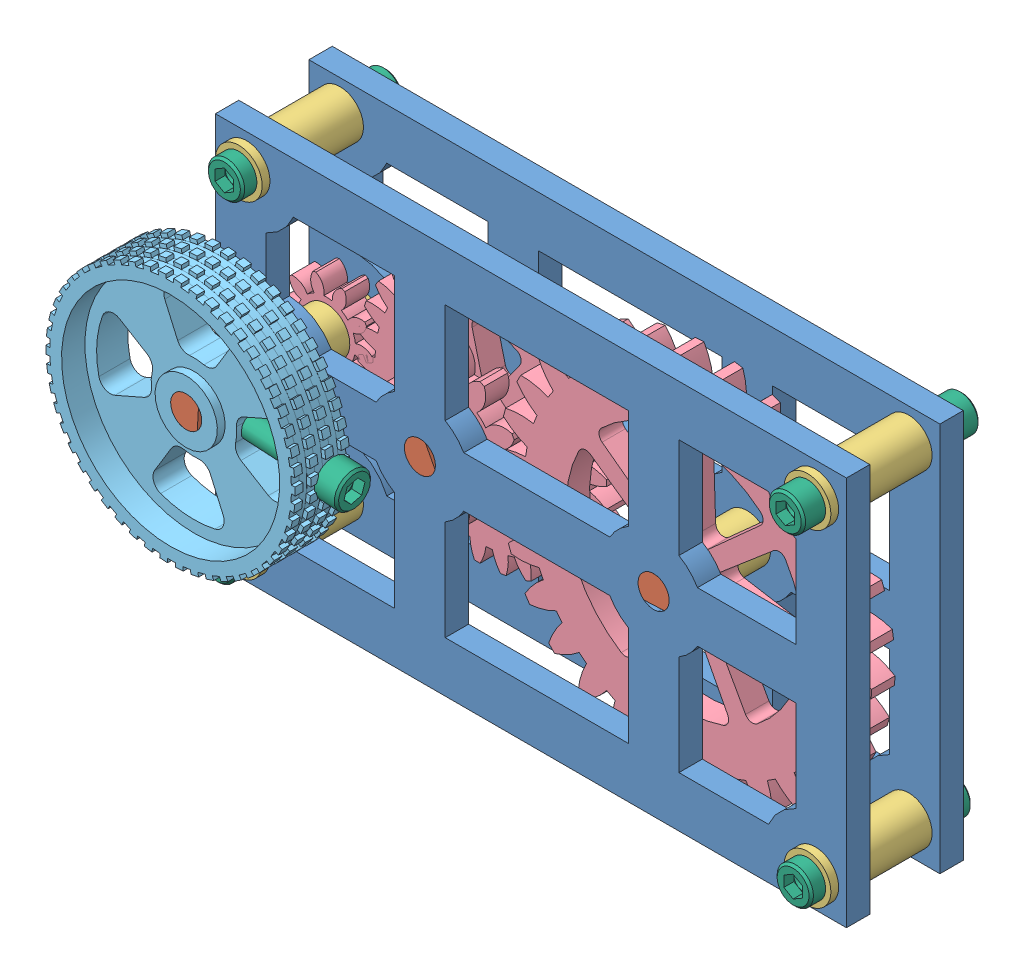
SolidWorks assembly Boxassem, configuration Default. Lengths in mm.
Overall size (91.84 50.13 37).
41 component instances, 6 part files, 57 mates.
Components (placement in the parent):
- gearbox-1: gearbox [Default] at (-8.9733 7.0729 77.188) size (81 50 3)
- subassem1-1: subassem1 [Default] at (-50.227 6.9916 109.6475) x (0.055794 0.998442 0) z (0 0 -1) size (11.53 12 25)
  - axle-1: axle [Long] at (0.4719 6.9883 7.4595) size (4 3.5 25)
  - spacer-1: spacer [1mm Tall] at (0.4719 6.9883 28.4595) x (0.18763 0.98224 0) z (0 0 1) size (6 6 1)
  - spacer-2: spacer [5mm Tall] at (0.4719 6.9883 20.4595) x (-0.596298 -0.802763 0) z (0 0 1) size (6 6 5)
  - root_gear-1: root_gear [10T 1.0Mod] at (0.4719 6.9883 25.4595) size (11.53 12 3)
- subassem2-1: subassem2 [Default] at (-30.4543 -3.0086 53.2509) x (0.46488 -0.885374 0) z (0 0 1) size (31.89 32 15)
  - axle-1: axle [Short] at (-5.5643 11.0888 23.9371) size (4 3.5 15)
  - root_gear-2: root_gear [30T 1.0Mod] at (-5.5643 11.0888 30.9371) x (-1 0 0) z (0 0 -1) size (31.89 32 3)
  - root_gear-3: root_gear [10T 1.5Mod] at (-5.5643 11.0888 31.9371) size (17.3 18 3)
  - spacer-1: spacer [1mm Tall] at (-5.5643 11.0888 34.9371) size (6 6 1)
  - spacer-2: spacer [1mm Tall] at (-5.5643 11.0888 30.9371) size (6 6 1)
  - spacer-3: spacer [4.2mm ID] at (-5.5643 11.0888 26.9371) size (6 6 1)
- subassem3-1: subassem3 [Default] at (11.1205 15.175 62.5804) x (-0.998971 -0.045347 0) z (0 0 1) size (47.84 48 25)
  - axle-1: axle [Long] at (4.7068 7.8968 4.6076) size (4 3.5 25)
  - root_gear-1: root_gear [30T 1.5Mod] at (4.7068 7.8968 22.6076) size (47.84 48 3)
  - spacer-1: spacer [4.2mm ID] at (4.7068 7.8968 25.6076) size (6 6 1)
  - spacer-3: spacer [5mm Tall] at (4.7068 7.8968 17.6076) size (6 6 5)
- gearbox-2: gearbox [Default] at (-8.9733 7.0729 89.188) size (81 50 3)
- knob-1: knob [Default] at (-43.2233 7.0729 97.188) x (0 0 1) z (-0.998442 0.055794 0) size (7 32 31.99)
- socket head cap screw_ai-8: socket head cap screw_ai [HX-SHCS 0.112-40x0.5625x0.5625-N] at (-24.62 6.0333 99.188) x (-0.998442 0.055794 0) z (-0.03971 -0.710622 0.702453) size (17.13 4.65 4.65)
- spacer-1: spacer [2.85mm ID] at (-45.4733 28.0729 80.188) size (6 6 9)
- spacer-2: spacer [1mm Tall] at (-45.4733 28.0729 92.188) x (0.882295 0.470697 0) z (0 0 1) size (6 6 1)
- spacer-3: spacer [2.85mm ID] at (-45.4733 -13.9271 80.188) size (6 6 9)
- spacer-4: spacer [1mm Tall] at (-45.4733 28.0729 76.188) x (0.877323 0.4799 0) z (0 0 1) size (6 6 1)
- spacer-5: spacer [2.85mm ID] at (27.5267 -13.9271 80.188) x (-0.974482 0.224464 0) z (0 0 1) size (6 6 9)
- spacer-6: spacer [2.85mm ID] at (27.5267 28.0729 80.188) x (0.88236 0.470576 0) z (0 0 1) size (6 6 9)
- spacer-7: spacer [1mm Tall] at (27.5267 28.0729 76.188) size (6 6 1)
- spacer-8: spacer [1mm Tall] at (27.5267 28.0729 92.188) size (6 6 1)
- spacer-9: spacer [1mm Tall] at (27.5267 -13.9271 76.188) x (0.973794 0.227431 0) z (0 0 1) size (6 6 1)
- spacer-10: spacer [1mm Tall] at (-45.4733 -13.9271 92.188) size (6 6 1)
- spacer-11: spacer [1mm Tall] at (27.5267 -13.9271 93.188) x (-0.923728 -0.383049 0) z (0 0 -1) size (6 6 1)
- spacer-12: spacer [1mm Tall] at (-45.4733 -13.9271 76.188) size (6 6 1)
- socket head cap screw_ai-11: socket head cap screw_ai [HX-SHCS 0.112-40x0.25x0.25-N] at (-45.4733 -13.9271 96.0328) x (0 0 -1) z (1 0 0) size (9.19 4.65 4.65)
- socket head cap screw_ai-12: socket head cap screw_ai [HX-SHCS 0.112-40x0.125x0.125-N] at (27.5267 -13.9271 95.0328) x (0 0 -1) z (1 0 0) size (6.02 4.65 4.65)
- socket head cap screw_ai-13: socket head cap screw_ai [HX-SHCS 0.112-40x0.125x0.125-N] at (27.5267 28.0729 96.0328) x (0 0 -1) z (1 0 0) size (6.02 4.65 4.65)
- socket head cap screw_ai-14: socket head cap screw_ai [HX-SHCS 0.112-40x0.125x0.125-N] at (-45.4733 28.0729 95.0328) x (0 0 -1) z (1 0 0) size (6.02 4.65 4.65)
- socket head cap screw_ai-16: socket head cap screw_ai [HX-SHCS 0.112-40x0.125x0.125-N] at (-45.4733 28.0729 74.3432) x (0 0 1) z (-1 0 0) size (6.02 4.65 4.65)
- socket head cap screw_ai-17: socket head cap screw_ai [HX-SHCS 0.112-40x0.125x0.125-N] at (27.5267 28.0729 73.3432) x (0 0 1) z (-1 0 0) size (6.02 4.65 4.65)
- socket head cap screw_ai-18: socket head cap screw_ai [HX-SHCS 0.112-40x0.125x0.125-N] at (27.5267 -13.9271 74.3432) x (0 0 1) z (-1 0 0) size (6.02 4.65 4.65)
- socket head cap screw_ai-20: socket head cap screw_ai [HX-SHCS 0.112-40x0.125x0.125-N] at (-45.4733 -13.9271 74.3432) x (0 0 1) z (-1 0 0) size (6.02 4.65 4.65)
Mates (geometry in assembly coordinates):
- Concentric1: concentric anti-aligned: cylinder of gearbox-1 through (-43.2233 7.0729 80.188) axis (0 0 -1) radius 2; cylinder of subassem1-1/axle-1 through (-43.2233 7.0729 77.188) axis (0 0 1) radius 2
- Coincident1: coincident anti-aligned: plane of gearbox-1 through (-8.9733 7.0729 80.188) normal (0 0 1); plane of subassem1-1/spacer-1 through (-43.2233 7.0729 80.188) normal (0 0 -1)
- Concentric2: concentric aligned: cylinder of gearbox-1 through (-23.2233 7.0729 80.188) axis (0 0 -1) radius 2; cylinder of subassem2-1/axle-1 through (-23.2233 7.0729 92.188) axis (0 0 -1) radius 2
- Coincident2: coincident anti-aligned: plane of gearbox-1 through (-8.9733 7.0729 80.188) normal (0 0 1); plane of subassem2-1/spacer-3 through (-23.2233 7.0729 80.188) normal (0 0 -1)
- GearMate1: gear = 10 : 30 mm: cylinder of subassem2-1/axle-1 through (-23.2233 7.0729 92.188) axis (0 0 -1) radius 2; cylinder of subassem1-1/axle-1 through (-43.2233 7.0729 77.188) axis (0 0 1) radius 2
- Parallel1: parallel aligned: plane of gearbox-1 through (-8.9733 7.0729 77.188) normal (0 0 -1); plane of subassem2-1/axle-1 through (-23.2233 7.0729 77.188) normal (0 0 -1)
- Concentric3: concentric aligned: cylinder of gearbox-1 through (6.7767 7.0729 80.188) axis (0 0 -1) radius 2; cylinder of subassem3-1/axle-1 through (6.7767 7.0729 92.188) axis (0 0 -1) radius 2
- Coincident4: coincident anti-aligned: plane of gearbox-1 through (-8.9733 7.0729 80.188) normal (0 0 1); plane of subassem3-1/spacer-3 through (6.7767 7.0729 80.188) normal (0 0 -1)
- GearMate2: gear = 10 : 30 mm: cylinder of subassem3-1/axle-1 through (6.7767 7.0729 92.188) axis (0 0 -1) radius 2; cylinder of subassem2-1/axle-1 through (-23.2233 7.0729 92.188) axis (0 0 -1) radius 2
- Concentric4: concentric aligned: cylinder of subassem3-1/axle-1 through (6.7767 7.0729 92.188) axis (0 0 -1) radius 2; cylinder of gearbox-2 through (6.7767 7.0729 92.188) axis (0 0 -1) radius 2
- Coincident5: coincident anti-aligned: plane of subassem3-1/spacer-1 through (6.7767 7.0729 89.188) normal (0 0 1); plane of gearbox-2 through (-8.9733 7.0729 89.188) normal (0 0 -1)
- Concentric5: concentric aligned: cylinder of subassem2-1/axle-1 through (-23.2233 7.0729 92.188) axis (0 0 -1) radius 2; cylinder of gearbox-2 through (-23.2233 7.0729 92.188) axis (0 0 -1) radius 2
- Concentric6: concentric anti-aligned: cylinder of subassem1-1/axle-1 through (-43.2233 7.0729 77.188) axis (0 0 1) radius 2; cylinder of knob-1 through (-43.2233 7.0729 97.188) axis (0 0 -1) radius 2
- Coincident6: coincident aligned: plane of subassem1-1/axle-1 through (-43.2233 7.0729 102.188) normal (0 0 1); plane of knob-1 through (-43.1117 9.0698 102.188) normal (0 0 1)
- Concentric7: concentric anti-aligned: cylinder of subassem1-1/axle-1 through (-43.2233 7.0729 77.188) axis (0 0 1) radius 2; cylinder of knob-1 through (-43.2233 7.0729 97.188) axis (0 0 -1) radius 2
- Concentric13: concentric anti-aligned: cylinder of knob-1 through (-43.2233 7.0729 99.188) axis (-0.998442 0.055794 0) radius 0.9; cylinder of socket head cap screw_ai-8 through (7.0805 4.2618 99.188) axis (0.998442 -0.055794 0) radius 1.4224
- Coincident12: coincident anti-aligned: plane of subassem1-1/axle-1 through (-41.7995 5.6684 77.188) normal (0.998442 -0.055794 0); plane of socket head cap screw_ai-8 through (-41.7666 6.257 98.445) normal (-0.998442 0.055794 0)
- Concentric15: concentric aligned: cylinder of gearbox-2 through (-45.4733 28.0729 92.188) axis (0 0 -1) radius 1.5; cylinder of spacer-2 through (-45.4733 28.0729 93.188) axis (0 0 -1) radius 2
- Coincident13: coincident anti-aligned: plane of gearbox-2 through (-8.9733 7.0729 92.188) normal (0 0 1); plane of spacer-2 through (-45.4733 28.0729 92.188) normal (0 0 -1)
- Concentric16: concentric aligned: cylinder of gearbox-1 through (-45.4733 28.0729 80.188) axis (0 0 -1) radius 1.5; cylinder of spacer-1 through (-45.4733 28.0729 89.188) axis (0 0 -1) radius 2
- Coincident14: coincident anti-aligned: plane of gearbox-1 through (-8.9733 7.0729 80.188) normal (0 0 1); plane of spacer-1 through (-45.4733 28.0729 80.188) normal (0 0 -1)
- Concentric17: concentric aligned: cylinder of gearbox-2 through (27.5267 28.0729 92.188) axis (0 0 -1) radius 1.5; cylinder of spacer-6 through (27.5267 28.0729 89.188) axis (0 0 -1) radius 2
- Coincident15: coincident anti-aligned: plane of gearbox-2 through (-8.9733 7.0729 89.188) normal (0 0 -1); plane of spacer-6 through (27.5267 28.0729 89.188) normal (0 0 1)
- Concentric18: concentric aligned: cylinder of gearbox-2 through (27.5267 -13.9271 92.188) axis (0 0 -1) radius 1.5; cylinder of spacer-5 through (27.5267 -13.9271 89.188) axis (0 0 -1) radius 2
- Coincident16: coincident anti-aligned: plane of gearbox-2 through (-8.9733 7.0729 89.188) normal (0 0 -1); plane of spacer-5 through (27.5267 -13.9271 89.188) normal (0 0 1)
- Concentric19: concentric aligned: cylinder of gearbox-2 through (-45.4733 -13.9271 92.188) axis (0 0 -1) radius 1.5; cylinder of spacer-3 through (-45.4733 -13.9271 89.188) axis (0 0 -1) radius 2
- Coincident17: coincident anti-aligned: plane of gearbox-2 through (-8.9733 7.0729 89.188) normal (0 0 -1); plane of spacer-3 through (-45.4733 -13.9271 89.188) normal (0 0 1)
- Concentric20: concentric aligned: cylinder of gearbox-1 through (-45.4733 28.0729 80.188) axis (0 0 -1) radius 1.5; cylinder of spacer-4 through (-45.4733 28.0729 77.188) axis (0 0 -1) radius 2
- Coincident18: coincident anti-aligned: plane of gearbox-1 through (-8.9733 7.0729 77.188) normal (0 0 -1); plane of spacer-4 through (-45.4733 28.0729 77.188) normal (0 0 1)
- Coincident19: coincident anti-aligned: plane of gearbox-1 through (-8.9733 7.0729 77.188) normal (0 0 -1); plane of spacer-7 through (27.5267 28.0729 77.188) normal (0 0 1)
- Concentric21: concentric aligned: cylinder of gearbox-1 through (27.5267 28.0729 80.188) axis (0 0 -1) radius 1.5; cylinder of spacer-7 through (27.5267 28.0729 77.188) axis (0 0 -1) radius 2
- Coincident20: coincident anti-aligned: plane of gearbox-2 through (-8.9733 7.0729 92.188) normal (0 0 1); plane of spacer-8 through (27.5267 28.0729 92.188) normal (0 0 -1)
- Concentric22: concentric aligned: cylinder of gearbox-2 through (27.5267 28.0729 92.188) axis (0 0 -1) radius 1.5; cylinder of spacer-8 through (27.5267 28.0729 93.188) axis (0 0 -1) radius 2
- Coincident22: coincident anti-aligned: plane of gearbox-2 through (-8.9733 7.0729 92.188) normal (0 0 1); plane of spacer-11 through (27.5267 -13.9271 92.188) normal (0 0 -1)
- Concentric23: concentric anti-aligned: cylinder of gearbox-2 through (27.5267 -13.9271 92.188) axis (0 0 -1) radius 1.5; cylinder of spacer-11 through (27.5267 -13.9271 92.188) axis (0 0 1) radius 2
- Concentric24: concentric aligned: cylinder of gearbox-1 through (27.5267 -13.9271 80.188) axis (0 0 -1) radius 1.5; cylinder of spacer-9 through (27.5267 -13.9271 77.188) axis (0 0 -1) radius 2
- Coincident23: coincident anti-aligned: plane of gearbox-1 through (-8.9733 7.0729 77.188) normal (0 0 -1); plane of spacer-9 through (27.5267 -13.9271 77.188) normal (0 0 1)
- Coincident24: coincident anti-aligned: plane of gearbox-1 through (-8.9733 7.0729 77.188) normal (0 0 -1); plane of spacer-12 through (-45.4733 -13.9271 77.188) normal (0 0 1)
- Coincident25: coincident anti-aligned: plane of gearbox-2 through (-8.9733 7.0729 92.188) normal (0 0 1); plane of spacer-10 through (-45.4733 -13.9271 92.188) normal (0 0 -1)
- Concentric25: concentric aligned: cylinder of gearbox-1 through (-45.4733 -13.9271 80.188) axis (0 0 -1) radius 1.5; cylinder of spacer-12 through (-45.4733 -13.9271 77.188) axis (0 0 -1) radius 2
- Concentric26: concentric aligned: cylinder of gearbox-2 through (-45.4733 -13.9271 92.188) axis (0 0 -1) radius 1.5; cylinder of spacer-10 through (-45.4733 -13.9271 93.188) axis (0 0 -1) radius 2
- Concentric27: concentric anti-aligned: cylinder of spacer-10 through (-45.4733 -13.9271 93.188) axis (0 0 -1) radius 2; cylinder of socket head cap screw_ai-11 through (-45.4733 -13.9271 127.7828) axis (0 0 1) radius 2.3241
- Coincident26: coincident anti-aligned: plane of spacer-10 through (-45.4733 -13.9271 93.188) normal (0 0 1); plane of socket head cap screw_ai-11 through (-45.4733 -11.603 93.188) normal (0 0 -1)
- Concentric28: concentric anti-aligned: cylinder of gearbox-2 through (27.5267 -13.9271 92.188) axis (0 0 -1) radius 1.5; cylinder of socket head cap screw_ai-12 through (27.5267 -13.9271 126.7828) axis (0 0 1) radius 2.3241
- Coincident27: coincident anti-aligned: plane of gearbox-2 through (-8.9733 7.0729 92.188) normal (0 0 1); plane of socket head cap screw_ai-12 through (27.5267 -11.603 92.188) normal (0 0 -1)
- Concentric29: concentric anti-aligned: cylinder of spacer-8 through (27.5267 28.0729 93.188) axis (0 0 -1) radius 2; cylinder of socket head cap screw_ai-13 through (27.5267 28.0729 127.7828) axis (0 0 1) radius 2.3241
- Coincident28: coincident anti-aligned: plane of spacer-8 through (27.5267 28.0729 93.188) normal (0 0 1); plane of socket head cap screw_ai-13 through (27.5267 30.397 93.188) normal (0 0 -1)
- Concentric30: concentric anti-aligned: cylinder of gearbox-2 through (-45.4733 28.0729 92.188) axis (0 0 -1) radius 1.5; cylinder of socket head cap screw_ai-14 through (-45.4733 28.0729 126.7828) axis (0 0 1) radius 2.3241
- Coincident29: coincident anti-aligned: plane of gearbox-2 through (-8.9733 7.0729 92.188) normal (0 0 1); plane of socket head cap screw_ai-14 through (-45.4733 30.397 92.188) normal (0 0 -1)
- Concentric32: concentric aligned: cylinder of gearbox-1 through (-45.4733 28.0729 80.188) axis (0 0 -1) radius 1.5; cylinder of socket head cap screw_ai-16 through (-45.4733 28.0729 42.5932) axis (0 0 -1) radius 2.3241
- Coincident31: coincident anti-aligned: plane of gearbox-1 through (-8.9733 7.0729 77.188) normal (0 0 -1); plane of socket head cap screw_ai-16 through (-45.4733 30.397 77.188) normal (0 0 1)
- Concentric33: concentric aligned: cylinder of spacer-7 through (27.5267 28.0729 77.188) axis (0 0 -1) radius 2; cylinder of socket head cap screw_ai-17 through (27.5267 28.0729 41.5932) axis (0 0 -1) radius 2.3241
- Coincident32: coincident anti-aligned: plane of spacer-7 through (27.5267 28.0729 76.188) normal (0 0 -1); plane of socket head cap screw_ai-17 through (27.5267 30.397 76.188) normal (0 0 1)
- Concentric34: concentric aligned: cylinder of gearbox-1 through (27.5267 -13.9271 80.188) axis (0 0 -1) radius 1.5; cylinder of socket head cap screw_ai-18 through (27.5267 -13.9271 42.5932) axis (0 0 -1) radius 2.3241
- Coincident33: coincident anti-aligned: plane of gearbox-1 through (-8.9733 7.0729 77.188) normal (0 0 -1); plane of socket head cap screw_ai-18 through (27.5267 -11.603 77.188) normal (0 0 1)
- Concentric36: concentric aligned: cylinder of gearbox-1 through (-45.4733 -13.9271 80.188) axis (0 0 -1) radius 1.5; cylinder of socket head cap screw_ai-20 through (-45.4733 -13.9271 42.5932) axis (0 0 -1) radius 2.3241
- Coincident34: coincident anti-aligned: plane of gearbox-1 through (-8.9733 7.0729 77.188) normal (0 0 -1); plane of socket head cap screw_ai-20 through (-45.4733 -11.603 77.188) normal (0 0 1)
